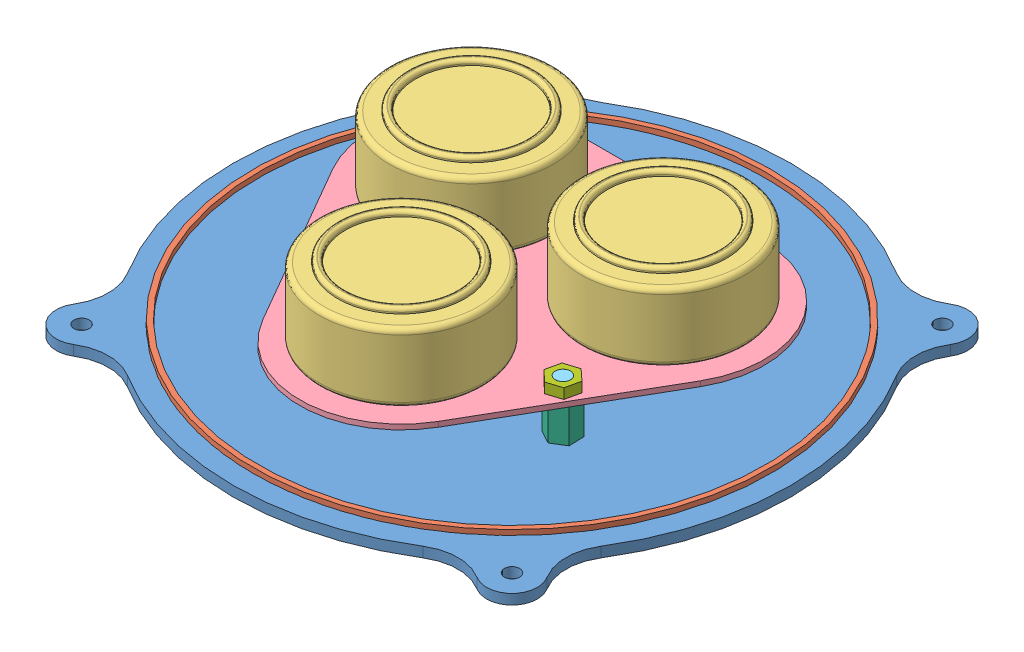
SolidWorks assembly ClipAssembly, configuration Default. Lengths in mm.
Overall size (143.51 26 143.51).
16 component instances, 7 part files, 23 mates.
Components (placement in the parent):
- Clip-1: Clip [Default] at origin size (110 2 110)
- Gasket-1: Gasket [Default] at (0 3 0) x (0.631829 0 0.775108) z (0.775108 0 -0.631829) size (102 2 102)
- Alphasense-1: Alphasense [Default] at (18.9035 10 -10.9139) x (-0.5 0 0.866025) z (-0.866025 0 -0.5) size (77.81 19.5 72.74)
  - Alphasense-1: Alphasense [Default] at origin size (32.33 14.5 32.33)
  - Alphasense-2: Alphasense [Default] at (37.807 0 0) size (32.33 14.5 32.33)
  - Alphasense-3: Alphasense [Default] at (18.9035 0 32.7418) size (32.33 14.5 32.33)
  - AlphasenseBoard-1: AlphasenseBoard [Default] at (18.9035 -1 10.9139) size (77.81 5 72.74)
- Thread-1: Thread [Default] at (-23.7412 0 13.707) x (-0.8278 0 -0.561024) z (0.561024 0 -0.8278) size (5 13.5 4.35)
- Thread-2: Thread [Default] at (0 0 -27.4139) x (-0.125019 0 0.992154) z (-0.992154 0 -0.125019) size (5 13.5 4.35)
- Thread-3: Thread [Default] at (23.7412 0 13.707) x (0.402458 0 0.915438) z (-0.915438 0 0.402458) size (5 13.5 4.35)
- ClipSeparator-1: ClipSeparator [Default] at (-23.7412 2 13.707) x (0.880706 0 0.473664) z (-0.473664 0 0.880706) size (5.29 7 6)
- ClipSeparator-2: ClipSeparator [Default] at (23.7412 2 13.707) size (5.29 7 6)
- ClipSeparator-3: ClipSeparator [Default] at (0 2 -27.4139) x (0.093101 0 0.995657) z (-0.995657 0 0.093101) size (5.29 7 6)
- ClipBolt-1: ClipBolt [Default] at (23.7412 12 13.707) x (-0.837169 0 -0.546944) z (-0.546944 0 0.837169) size (5.92 2 5.62)
- ClipBolt-2: ClipBolt [Default] at (-23.7412 10 13.707) size (5.92 2 5.62)
- ClipBolt-3: ClipBolt [Default] at (0 10 -27.4139) size (5.92 2 5.62)
Mates (geometry in assembly coordinates):
- Concentric1: concentric aligned: cylinder of Clip-1 through (0 1 0) axis (0 1 0) radius 51; cylinder of Gasket-1 through (0 1 0) axis (0 1 0) radius 51
- Coincident1: coincident anti-aligned: plane of Clip-1 through (0 1 0) normal (0 1 0); plane of Gasket-1 through (0 1 0) normal (0 -1 0)
- Concentric7: concentric aligned: cylinder of Thread-1 through (-23.7412 12 13.707) axis (0 -1 0) radius 1.5; cylinder of ClipSeparator-1 through (-23.7412 9 13.707) axis (0 -1 0) radius 1.5
- Coincident6: coincident anti-aligned: plane of Alphasense-1/AlphasenseBoard-1 through (18.9035 9 -10.9139) normal (0 -1 0); plane of ClipSeparator-1 through (-23.7412 9 13.707) normal (0 1 0)
- Coincident7: coincident anti-aligned: plane of Alphasense-1/AlphasenseBoard-1 through (18.9035 9 -10.9139) normal (0 -1 0); plane of ClipSeparator-2 through (23.7412 9 13.707) normal (0 1 0)
- Coincident8: coincident anti-aligned: plane of Alphasense-1/AlphasenseBoard-1 through (18.9035 9 -10.9139) normal (0 -1 0); plane of ClipSeparator-3 through (0 9 -27.4139) normal (0 1 0)
- Concentric8: concentric aligned: cylinder of Thread-3 through (23.7412 12 13.707) axis (0 -1 0) radius 1.5; cylinder of ClipSeparator-2 through (23.7412 9 13.707) axis (0 -1 0) radius 1.5
- Concentric10: concentric aligned: cylinder of Thread-2 through (0 12 -27.4139) axis (0 -1 0) radius 1.5; cylinder of ClipSeparator-3 through (0 9 -27.4139) axis (0 -1 0) radius 1.5
- Coincident10: coincident anti-aligned: plane of Alphasense-1/AlphasenseBoard-1 through (18.9035 10 -10.9139) normal (0 1 0); plane of ClipBolt-1 through (23.7412 10 13.707) normal (0 -1 0)
- Coincident11: coincident anti-aligned: plane of Alphasense-1/AlphasenseBoard-1 through (18.9035 10 -10.9139) normal (0 1 0); plane of ClipBolt-3 through (0 10 -27.4139) normal (0 -1 0)
- Coincident12: coincident aligned: plane of ClipBolt-2 through (-23.7412 10 13.707) normal (0 -1 0); plane of ClipBolt-3 through (0 10 -27.4139) normal (0 -1 0)
- Concentric11: concentric anti-aligned: cylinder of Thread-3 through (23.7412 12 13.707) axis (0 -1 0) radius 1.5; cylinder of ClipBolt-1 through (23.7412 10 13.707) axis (0 1 0) radius 1.5
- Concentric12: concentric aligned: cylinder of Thread-1 through (-23.7412 12 13.707) axis (0 -1 0) radius 1.5; cylinder of ClipBolt-2 through (-23.7412 12 13.707) axis (0 -1 0) radius 1.5
- Concentric13: concentric aligned: cylinder of Thread-2 through (0 12 -27.4139) axis (0 -1 0) radius 1.5; cylinder of ClipBolt-3 through (0 12 -27.4139) axis (0 -1 0) radius 1.5
- Coincident13: coincident anti-aligned: plane of Clip-1 through (-48.7756 2 -38.4342) normal (0 1 0); plane of ClipSeparator-3 through (0 2 -27.4139) normal (0 -1 0)
- Concentric18: concentric aligned: cylinder of Alphasense-1/AlphasenseBoard-1 through (0 10 -27.4139) axis (0 -1 0) radius 1.5; cylinder of Thread-2 through (0 12 -27.4139) axis (0 -1 0) radius 1.5
- Concentric19: concentric aligned: cylinder of Clip-1 through (0 2 -27.4139) axis (0 -1 0) radius 1.5; cylinder of Thread-2 through (0 12 -27.4139) axis (0 -1 0) radius 1.5
- Concentric20: concentric aligned: cylinder of Clip-1 through (-23.7412 2 13.707) axis (0 -1 0) radius 1.5; cylinder of Thread-1 through (-23.7412 12 13.707) axis (0 -1 0) radius 1.5
- Concentric21: concentric aligned: cylinder of Clip-1 through (23.7412 2 13.707) axis (0 -1 0) radius 1.5; cylinder of Thread-3 through (23.7412 12 13.707) axis (0 -1 0) radius 1.5
- Concentric22: concentric aligned: cylinder of Alphasense-1/AlphasenseBoard-1 through (-23.7412 10 13.707) axis (0 -1 0) radius 1.5; cylinder of Thread-1 through (-23.7412 12 13.707) axis (0 -1 0) radius 1.5
- Coincident14: coincident anti-aligned: plane of Clip-1 through (-48.7756 0 -38.4342) normal (0 -1 0); plane of Thread-1 through (-23.7412 0 13.707) normal (0 1 0)
- Coincident15: coincident anti-aligned: plane of Clip-1 through (-48.7756 0 -38.4342) normal (0 -1 0); plane of Thread-2 through (0 0 -27.4139) normal (0 1 0)
- Coincident16: coincident anti-aligned: plane of Clip-1 through (-48.7756 0 -38.4342) normal (0 -1 0); plane of Thread-3 through (23.7412 0 13.707) normal (0 1 0)
